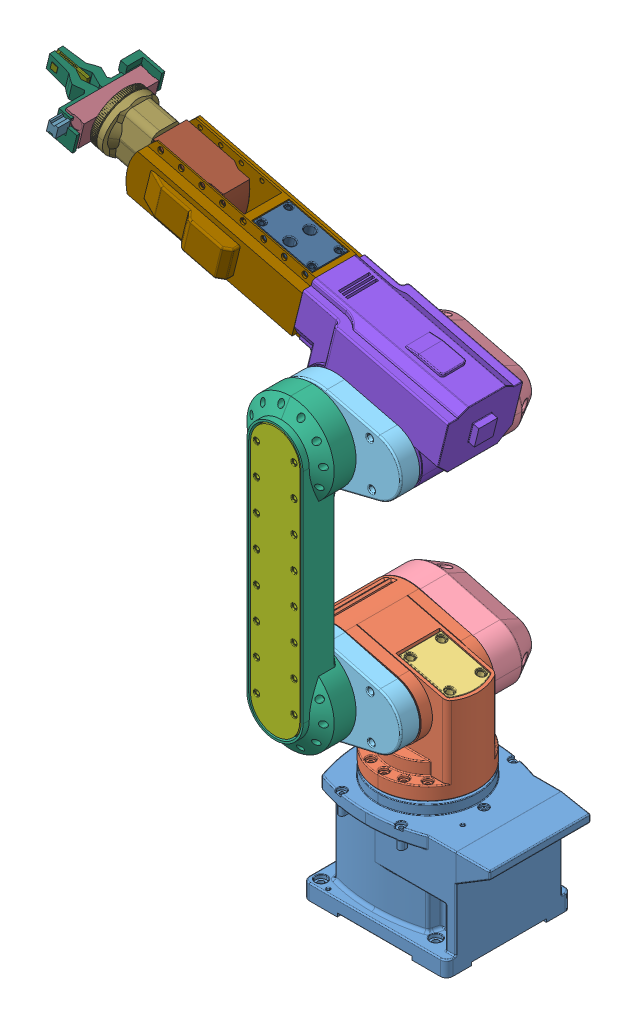
SolidWorks assembly movable step 4, configuration Default. Lengths in mm.
Overall size (786.84 890.65 303.13).
20 component instances, 16 part files, 57 mates.
Components (placement in the parent):
- Base.step-1: Base.step [Default] at (50.4601 21.8888 234.5287) size (280 185 200)
- Joint_1.step-1: Joint_1.step [Default] at (68.2167 333.4398 234.5287) size (242.75 189 160)
- Joint_1_top_cap.step-1: Joint_1_top_cap.step [Default] at (70.5148 316.8888 234.5287) x (1 0 0) z (0 1 0) size (91.2 70 52.34)
- Part3.step-1: Part3.step [Default] at (63.4179 21.928 234.5287) x (0.999815 -0.016322 -0.010154) z (0.010153 -0.000166 0.999948) size (205.53 137 83.39)
- Part4.step-1: Part4.step [Default] at (63.4179 21.928 234.5287) x (0.999815 -0.016322 -0.010154) z (0.010153 -0.000166 0.999948) size (205.37 137 45.97)
- Joint_2.step-1: Joint_2.step [Default] at (-21.7667 647.378 238.6434) x (0 -0.999953 -0.009698) z (0.003009 -0.009698 0.999948) size (490.3 140.11 64.56)
- joint_2_cap.step-1: joint_2_cap.step [Default] at (-275.8903 144.2787 234.5287) x (0.296333 -0.955031 -0.010154) z (0.003009 -0.009698 0.999948) size (415.27 184.72 18.75)
- Part3.step-2: Part3.step [Default] at (68.4534 373.4102 234.5287) x (0.999948 0.000764 -0.010154) z (0.010154 0.000008 0.999948) size (205.53 137 83.39)
- Part4.step-2: Part4.step [Default] at (68.4534 373.4102 234.5287) x (0.999948 0.000764 -0.010154) z (0.010154 0.000008 0.999948) size (205.37 137 45.97)
- Part5.step-1: Part5.step [Default] at (24.1084 630.1919 238.2942) x (0.970756 -0.239852 -0.010154) z (0.009858 -0.002436 0.999948) size (270.42 212 122.27)
- Joint_3_front^industry_robot_arm_3.step-1: Joint_3_front^industry_robot_arm_3.step [Default] at (-224.4166 709.3124 234.7907) x (0.970807 -0.239864 0) z (0 0 1) size (280 99.67 120)
- Joint_3_top_cap^industry_robot_arm_3.step-1: Joint_3_top_cap^industry_robot_arm_3.step [Default] at (295.0467 179.5597 234.7907) x (0.970807 -0.239864 0) z (0 0 1) size (97 20 57)
- joint_4^industry_robot_arm_3.step-1: joint_4^industry_robot_arm_3.step [Default] at (-554.8076 967.2397 234.7907) x (-0.970807 0.239864 0) z (0 0 1) size (126.86 92 60)
- joint_4_front^industry_robot_arm_3.step-1: joint_4_front^industry_robot_arm_3.step [Default] at (-401.6939 796.0726 78.0925) x (0 0 -1) z (0.970807 -0.239864 0) size (88 89.06 70)
- joint_4_super_front^industry_robot_arm_3.step-1: joint_4_super_front^industry_robot_arm_3.step [Default] at (-447.1433 778.8854 -119.2569) x (0 0 1) z (-0.970807 0.239864 0) size (120 40 40)
- joint_4_super_front_middle^industry_robot_arm_3.step-1: joint_4_super_front_middle^industry_robot_arm_3.step [Default] at (-467.3861 778.2523 -180.2963) x (0 0 1) z (-0.970807 0.239864 0) size (160 18 25)
- Gripper_left^industry_robot_arm_3.step-1: Gripper_left^industry_robot_arm_3.step [Default] at (410.0528 507.9058 373.8777) x (0.970807 -0.239864 0) z (0 0 1) size (105.79 39 65)
- Gripper_left^industry_robot_arm_3.step-2: Gripper_left^industry_robot_arm_3.step [Default] at (477.8722 782.3926 90.6237) x (0.970807 -0.239864 0) z (0 0 -1) size (105.79 39 65)
- Gripper_right_grip^industry_robot_arm_3.step-1: Gripper_right_grip^industry_robot_arm_3.step [Default] at (542.6596 1119.0264 2282.2226) x (-0.954279 0.23578 -0.183739) z (-0.178375 0.044072 0.982975) size (52.87 24 20.92)
- Gripper_right_grip^industry_robot_arm_3.step-2: Gripper_right_grip^industry_robot_arm_3.step [Default] at (310.607 179.8353 -1817.7211) x (-0.954279 0.23578 0.183739) z (-0.178375 0.044072 -0.982975) size (52.87 24 20.92)
Mates (geometry in assembly coordinates):
- Concentric1: concentric aligned: cylinder of Base.step-1 through (68.2167 206.8888 234.5287) axis (0 -1 0) radius 80; cylinder of Joint_1.step-1 through (68.2167 222.8888 234.5287) axis (0 -1 0) radius 69
- Coincident1: coincident anti-aligned: plane of Base.step-1 through (68.2167 196.8888 234.5287) normal (0 1 0); plane of Joint_1.step-1 through (68.2167 196.8888 234.5287) normal (0 -1 0)
- Parallel1: parallel aligned: plane of Base.step-1 through (198.2167 111.8888 319.5287) normal (0 0 1); plane of Joint_1.step-1 through (68.2167 333.4398 274.5287) normal (0 0 1)
- Coincident2: coincident anti-aligned: plane of Joint_1.step-1 through (68.2167 316.8888 234.5287) normal (0 1 0); plane of Joint_1_top_cap.step-1 through (70.5148 316.8888 234.5287) normal (0 -1 0)
- Concentric3: concentric aligned: cylinder of Joint_1.step-1 through (68.2167 385.8888 234.5287) axis (0 -1 0) radius 75; cylinder of Joint_1_top_cap.step-1 through (68.2167 470.6805 234.5287) axis (0 -1 0) radius 75.4393
- Parallel2: parallel anti-aligned: plane of Joint_1.step-1 through (52.0118 385.8888 269.5287) normal (1 0 0); plane of Joint_1_top_cap.step-1 through (55.8099 470.6805 201.0287) normal (-1 0 0)
- Coincident3: coincident anti-aligned: plane of Joint_1.step-1 through (68.2167 333.4398 174.5287) normal (0 0 -1); plane of Part3.step-1 through (68.2167 315.8888 174.5287) normal (0 0 1)
- Concentric4: concentric anti-aligned: cylinder of Joint_1.step-1 through (68.2167 315.8888 274.5287) axis (0 0 -1) radius 48.4134; cylinder of Part3.step-1 through (68.2167 315.8888 94.5287) axis (0 0 1) radius 46.9225
- Tangent1: tangent aligned: cylinder of Joint_1.step-1 through (-21.7787 315.8888 274.5287) axis (0 0 -1) radius 70; cylinder of Part3.step-1 through (-21.4511 317.3526 94.5287) axis (0 0 1) radius 68.5
- Coincident4: coincident anti-aligned: plane of Joint_1.step-1 through (68.2167 333.4398 294.5287) normal (0 0 1); plane of Part4.step-1 through (68.2167 315.8888 294.5287) normal (0 0 -1)
- Concentric6: concentric aligned: cylinder of Joint_1.step-1 through (68.2167 315.8888 274.5287) axis (0 0 -1) radius 48.4134; cylinder of Part4.step-1 through (68.2167 315.8888 324.5287) axis (0 0 -1) radius 46.9225
- Tangent2: tangent aligned: cylinder of Joint_1.step-1 through (-21.7787 315.8888 274.5287) axis (0 0 -1) radius 70; cylinder of Part4.step-1 through (-21.4511 317.3526 324.5287) axis (0 0 -1) radius 68.5
- Coincident5: coincident anti-aligned: plane of Part4.step-1 through (-21.7667 317.3577 329.5287) normal (0 0 1); plane of Joint_2.step-1 through (-21.7667 317.3577 329.5287) normal (0 0 -1)
- Concentric7: concentric aligned: cylinder of Part4.step-1 through (-21.7667 317.3577 339.5287) axis (0 0 -1) radius 30; cylinder of Joint_2.step-1 through (-21.7667 317.3577 339.5287) axis (0 0 -1) radius 30
- Parallel3: parallel aligned: plane of Base.step-1 through (198.2167 46.8888 134.5287) normal (1 0 0); plane of Joint_2.step-1 through (23.2333 667.3413 339.5287) normal (1 0 0)
- Concentric8: concentric anti-aligned: cylinder of Joint_2.step-1 through (-21.7667 317.3577 374.5287) axis (0 0 1) radius 42; cylinder of joint_2_cap.step-1 through (-21.7667 317.3577 389.0687) axis (0 0 -1) radius 39.5
- Coincident6: coincident anti-aligned: plane of Joint_2.step-1 through (-21.7667 667.3413 374.5287) normal (0 0 1); plane of joint_2_cap.step-1 through (-21.7667 317.3577 374.5287) normal (0 0 -1)
- Concentric9: concentric anti-aligned: cylinder of Joint_2.step-1 through (-21.7667 667.3413 374.5287) axis (0 0 1) radius 42; cylinder of joint_2_cap.step-1 through (-21.7667 667.3413 389.0687) axis (0 0 -1) radius 39.5
- Coincident7: coincident anti-aligned: plane of Joint_2.step-1 through (-21.7667 667.3413 329.5287) normal (0 0 -1); plane of Part4.step-2 through (-21.7667 667.3413 329.5287) normal (0 0 1)
- Concentric10: concentric aligned: cylinder of Joint_2.step-1 through (-21.7667 667.3413 339.5287) axis (0 0 -1) radius 30; cylinder of Part4.step-2 through (-21.7667 667.3413 339.5287) axis (0 0 -1) radius 30
- Concentric11: concentric anti-aligned: cylinder of Part4.step-2 through (68.2286 667.4101 324.5287) axis (0 0 -1) radius 46.9225; cylinder of Part5.step-1 through (68.2286 667.4101 174.5287) axis (0 0 1) radius 46.9225
- Coincident8: coincident anti-aligned: plane of Part4.step-2 through (68.2286 667.4101 294.5287) normal (0 0 -1); plane of Part5.step-1 through (68.2286 667.4101 294.5287) normal (0 0 1)
- Concentric12: concentric anti-aligned: cylinder of Part4.step-2 through (-21.4511 667.3415 324.5287) axis (0 0 -1) radius 68.5; cylinder of Part5.step-1 through (-21.4511 667.3415 174.5287) axis (0 0 1) radius 68.5
- Coincident9: coincident anti-aligned: plane of Part3.step-2 through (68.2286 667.4101 174.5287) normal (0 0 1); plane of Part5.step-1 through (68.2286 667.4101 174.5287) normal (0 0 -1)
- Concentric13: concentric aligned: cylinder of Part3.step-2 through (-21.4511 667.3415 94.5287) axis (0 0 1) radius 68.5; cylinder of Part5.step-1 through (-21.4511 667.3415 174.5287) axis (0 0 1) radius 68.5
- Tangent3: tangent aligned: cylinder of Part3.step-2 through (68.2286 667.4101 94.5287) axis (0 0 1) radius 46.9225; cylinder of Part5.step-1 through (68.2286 667.4101 174.5287) axis (0 0 1) radius 46.9225
- Parallel4: parallel aligned: plane of Joint_1.step-1 through (75.7423 363.8986 274.5287) normal (0.239864 0.970807 0); plane of Part5.step-1 through (-25.6032 811.0323 179.5287) normal (0.239864 0.970807 0)
- Coincident10: coincident anti-aligned: plane of Part5.step-1 through (-102.9867 727.1449 184.5287) normal (-0.970807 0.239864 0); plane of Joint_3_front^industry_robot_arm_3.step-1 through (-79.0405 824.0629 284.7907) normal (0.970807 -0.239864 0)
- Concentric14: concentric aligned: cylinder of Part5.step-1 through (-100.7016 778.0838 234.5287) axis (0.970807 -0.239864 0) radius 30; cylinder of Joint_3_front^industry_robot_arm_3.step-1 through (-100.7016 778.0838 234.5287) axis (0.970807 -0.239864 0) radius 30
- Distance1: distance = 1.5 mm anti-aligned: plane of Joint_3_top_cap^industry_robot_arm_3.step-1 through (-182.4314 849.6084 206.2907) normal (-0.970807 0.239864 0); plane of Joint_3_front^industry_robot_arm_3.step-1 through (-188.6849 830.5521 204.7907) normal (0.970807 -0.239864 0)
- Distance3: distance = 1.5 mm anti-aligned: plane of Joint_3_top_cap^industry_robot_arm_3.step-1 through (-182.4314 849.6084 263.2907) normal (0 0 1); plane of Joint_3_front^industry_robot_arm_3.step-1 through (-188.6849 830.5521 264.7907) normal (0 0 -1)
- Coincident13: coincident anti-aligned: plane of Joint_3_front^industry_robot_arm_3.step-1 through (-194.1287 831.8972 234.7907) normal (0.239864 0.970807 0); plane of Joint_3_top_cap^industry_robot_arm_3.step-1 through (418.8064 680.455 234.7907) normal (-0.239864 -0.970807 0)
- Parallel5: parallel aligned: plane of Part5.step-1 through (-102.9867 727.1449 284.5287) normal (0 0 1); plane of Joint_3_front^industry_robot_arm_3.step-1 through (-224.4166 709.3124 284.7907) normal (0 0 1)
- Concentric15: concentric anti-aligned: cylinder of Joint_3_front^industry_robot_arm_3.step-1 through (-315.373 832.7636 264.7907) axis (0 0 -1) radius 30; cylinder of joint_4^industry_robot_arm_3.step-1 through (-315.373 832.7636 204.7907) axis (0 0 1) radius 30
- Coincident14: coincident anti-aligned: plane of Joint_3_front^industry_robot_arm_3.step-1 through (-495.1524 824.2125 264.7907) normal (0 0 -1); plane of joint_4^industry_robot_arm_3.step-1 through (-554.8076 967.2397 264.7907) normal (0 0 1)
- Coincident15: coincident anti-aligned: plane of joint_4^industry_robot_arm_3.step-1 through (-346.3749 915.7408 234.7907) normal (-0.970807 0.239864 0); plane of joint_4_front^industry_robot_arm_3.step-1 through (-377.4237 790.076 78.0925) normal (0.970807 -0.239864 0)
- Coincident19: coincident anti-aligned: plane of joint_4^industry_robot_arm_3.step-1 through (-360.3154 859.3189 249.7907) normal (0.239864 0.970807 0); plane of joint_4_front^industry_robot_arm_3.step-1 through (-360.3154 859.3189 249.7907) normal (-0.239864 -0.970807 0)
- Coincident20: coincident anti-aligned: plane of joint_4^industry_robot_arm_3.step-1 through (-367.5113 830.1947 249.7907) normal (0 0 1); plane of joint_4_front^industry_robot_arm_3.step-1 through (-360.3154 859.3189 249.7907) normal (0 0 -1)
- Coincident21: coincident anti-aligned: plane of joint_4_front^industry_robot_arm_3.step-1 through (-430.8181 803.2685 78.0925) normal (-0.970807 0.239864 0); plane of joint_4_super_front^industry_robot_arm_3.step-1 through (-437.4353 776.4867 -119.2569) normal (0.970807 -0.239864 0)
- Coincident22: coincident anti-aligned: plane of joint_4_front^industry_robot_arm_3.step-1 through (-413.7098 872.5114 219.7907) normal (0 0 1); plane of joint_4_super_front^industry_robot_arm_3.step-1 through (-420.9057 843.3872 219.7907) normal (0 0 -1)
- Coincident23: coincident anti-aligned: plane of joint_4_front^industry_robot_arm_3.step-1 through (-413.7098 872.5114 219.7907) normal (-0.239864 -0.970807 0); plane of joint_4_super_front^industry_robot_arm_3.step-1 through (-413.7098 872.5114 249.7907) normal (0.239864 0.970807 0)
- Coincident24: coincident anti-aligned: plane of joint_4_super_front^industry_robot_arm_3.step-1 through (-456.366 781.1641 -119.2569) normal (-0.970807 0.239864 0); plane of joint_4_super_front_middle^industry_robot_arm_3.step-1 through (-457.6781 775.8536 -180.2963) normal (0.970807 -0.239864 0)
- Coincident25: coincident anti-aligned: plane of joint_4_super_front^industry_robot_arm_3.step-1 through (-435.0391 867.4807 239.7907) normal (0 0 -1); plane of joint_4_super_front_middle^industry_robot_arm_3.step-1 through (-435.0391 867.4807 239.7907) normal (0 0 1)
- Coincident26: coincident anti-aligned: plane of joint_4_super_front^industry_robot_arm_3.step-1 through (-435.0391 867.4807 229.7907) normal (-0.239864 -0.970807 0); plane of joint_4_super_front_middle^industry_robot_arm_3.step-1 through (-435.0391 867.4807 239.7907) normal (0.239864 0.970807 0)
- Coincident27: coincident anti-aligned: plane of joint_4_super_front_middle^industry_robot_arm_3.step-1 through (-481.9482 781.8502 -180.2963) normal (-0.970807 0.239864 0); plane of Gripper_left^industry_robot_arm_3.step-1 through (-458.3498 877.3605 332.4226) normal (0.970807 -0.239864 0)
- Coincident28: coincident anti-aligned: plane of joint_4_super_front_middle^industry_robot_arm_3.step-1 through (-458.2395 861.3671 154.7907) normal (-0.239864 -0.970807 0); plane of Gripper_left^industry_robot_arm_3.step-1 through (-458.2395 861.3671 332.4226) normal (0.239864 0.970807 0)
- Parallel6: parallel aligned: plane of Joint_3_top_cap^industry_robot_arm_3.step-1 through (423.6037 699.8711 234.7907) normal (0.239864 0.970807 0); plane of joint_4^industry_robot_arm_3.step-1 through (-228.114 852.4067 264.7907) normal (0.239864 0.970807 0)
- Coincident29: coincident anti-aligned: plane of joint_4_super_front_middle^industry_robot_arm_3.step-1 through (-481.9482 781.8502 -180.2963) normal (-0.970807 0.239864 0); plane of Gripper_left^industry_robot_arm_3.step-2 through (-462.6674 859.886 207.3426) normal (0.970807 -0.239864 0)
- Coincident30: coincident anti-aligned: plane of joint_4_super_front_middle^industry_robot_arm_3.step-1 through (-458.2395 861.3671 154.7907) normal (-0.239864 -0.970807 0); plane of Gripper_left^industry_robot_arm_3.step-2 through (-453.3854 860.1678 207.3426) normal (0.239864 0.970807 0)
- Coincident31: coincident anti-aligned: plane of Gripper_left^industry_robot_arm_3.step-1 through (-501.1855 866.3127 272.4226) normal (0 0 -1); plane of Gripper_right_grip^industry_robot_arm_3.step-1 through (542.6596 1119.0264 272.4226) normal (0 0 1)
- Coincident34: coincident anti-aligned: plane of Gripper_left^industry_robot_arm_3.step-2 through (-495.4288 889.6121 267.3426) normal (0 0 1); plane of Gripper_right_grip^industry_robot_arm_3.step-2 through (310.607 179.8353 267.3426) normal (0 0 -1)
- Coincident35: coincident anti-aligned: plane of Gripper_left^industry_robot_arm_3.step-1 through (-524.1532 889.4987 282.4226) normal (0.970807 -0.239864 0); plane of Gripper_right_grip^industry_robot_arm_3.step-1 through (-526.5518 879.7907 282.4226) normal (-0.970807 0.239864 0)
- Coincident36: coincident anti-aligned: plane of Gripper_left^industry_robot_arm_3.step-1 through (-514.4451 887.1001 282.4226) normal (-0.239864 -0.970807 0); plane of Gripper_right_grip^industry_robot_arm_3.step-1 through (-514.4451 887.1001 282.4226) normal (0.239864 0.970807 0)
- Coincident37: coincident anti-aligned: plane of Gripper_left^industry_robot_arm_3.step-2 through (-516.8438 877.392 257.3426) normal (0.239864 0.970807 0); plane of Gripper_right_grip^industry_robot_arm_3.step-2 through (-516.8438 877.392 257.3426) normal (-0.239864 -0.970807 0)
- Coincident38: coincident anti-aligned: plane of Gripper_left^industry_robot_arm_3.step-2 through (-516.8438 877.392 257.3426) normal (-0.970807 0.239864 0); plane of Gripper_right_grip^industry_robot_arm_3.step-2 through (-514.4451 887.1001 257.3426) normal (0.970807 -0.239864 0)
- Coincident39: coincident anti-aligned: plane of Gripper_right_grip^industry_robot_arm_3.step-1 through (542.6596 1119.0264 269.8826) normal (0 0 -1); plane of Gripper_right_grip^industry_robot_arm_3.step-2 through (310.607 179.8353 269.8826) normal (0 0 1)
- Coincident40: coincident anti-aligned: plane of joint_4_super_front^industry_robot_arm_3.step-1 through (-451.3427 886.96 294.7907) normal (0 0 1); plane of Gripper_left^industry_robot_arm_3.step-1 through (410.0528 507.9058 332.4226) normal (0 0 -1)
